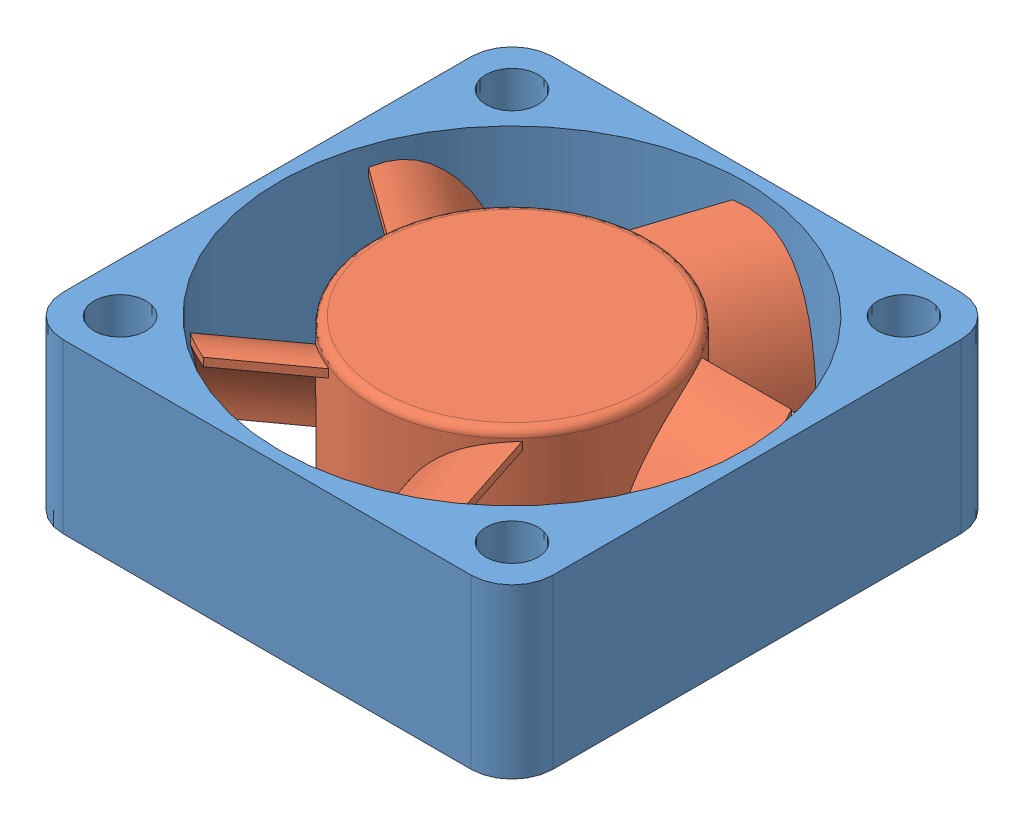
SolidWorks assembly 1313-Z1P-A_2, configuration Default. Lengths in mm.
Overall size (30 10.3 30).
2 component instances, 2 part files, 0 mates.
Components (placement in the parent):
- Fan Base 30x30-1: Fan Base 30x30 [Default] at (1.9775 7.6443 16.6801) size (30 10.3 30)
- Fan Rotor 30x30-1: Fan Rotor 30x30 [Default] at (1.9775 9.9443 16.6801) size (26.91 8.35 27.44)
